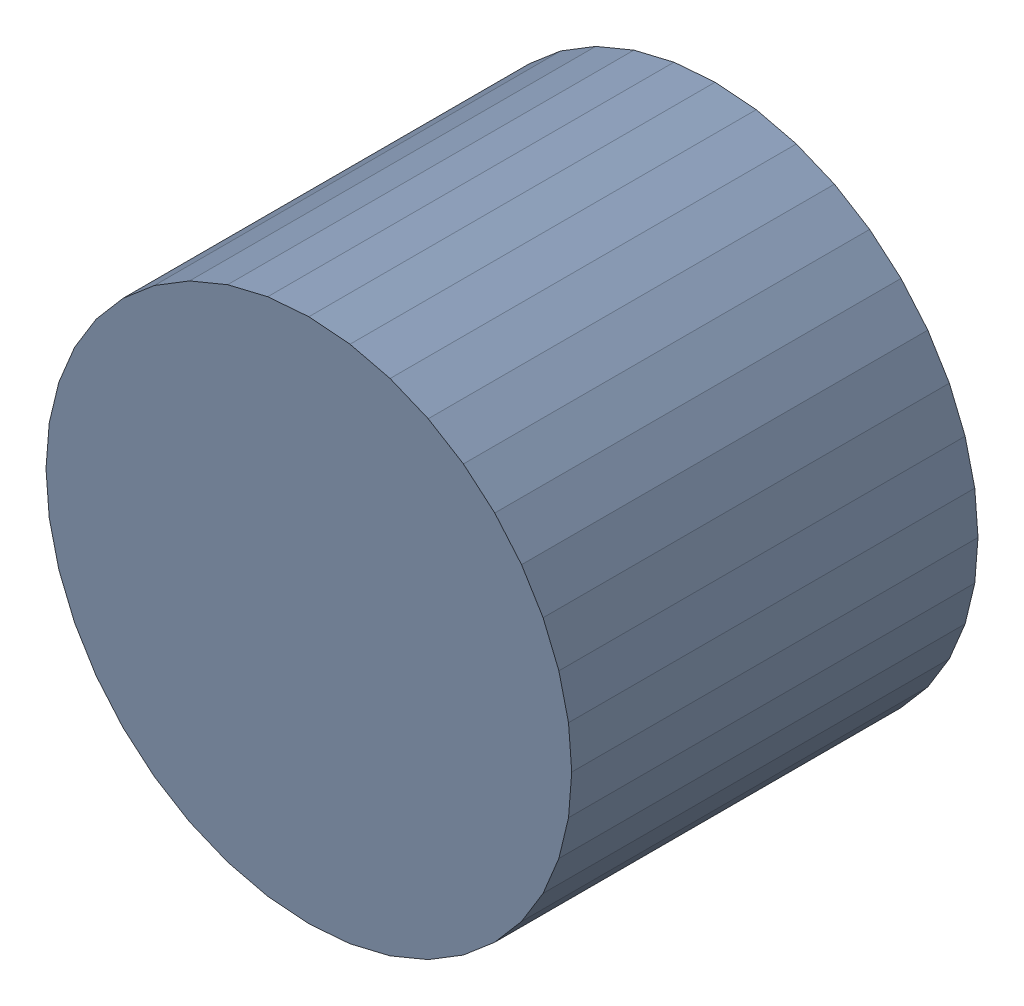
SolidWorks assembly C22Kanaloa_v2.0.0_Power, configuration Default. Lengths in mm.
Overall size (8.02 8.02 6.2).
2 component instances, 1 part files, 0 mates.
Components (placement in the parent):
- 425994496-1: 425994496 [Default] at (124.689 160.68 0) size (8.02 8.02 6.2)
  - Extruded_22-1: Extruded_22 [Default] at origin size (8.02 8.02 6.2)
